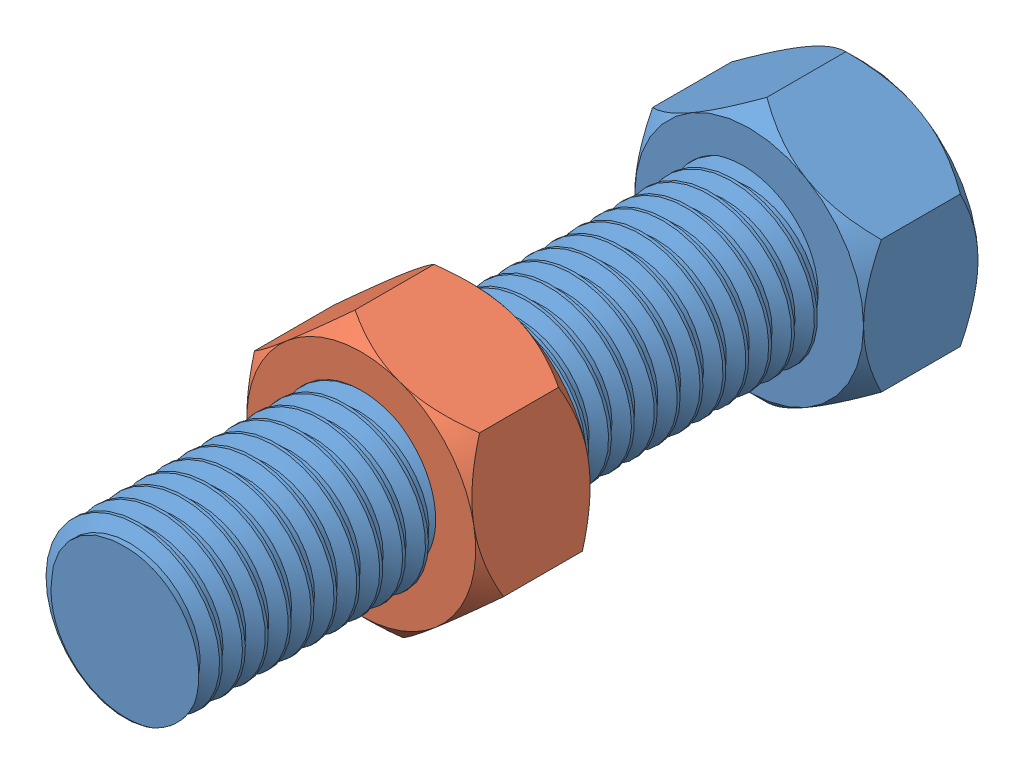
SolidWorks assembly Assem1, configuration Default. Lengths in mm.
Overall size (16.15 15.85 32.98).
2 component instances, 2 part files, 3 mates.
Components (placement in the parent):
- bolt-1: bolt [Default] at (11.5962 19.1086 10.4136) size (10 12.7 32.98)
- nut-1: nut [Default] at (11.5962 19.1086 27.3665) x (-0.648719 0.761028 0) z (0 0 1) size (10 12.7 5.69)
Mates (geometry in assembly coordinates):
- Concentric1: concentric: circle of bolt-1; circle of nut-1
- LimitDistance1: limit distance = 11.9529 mm: plane of nut-1 through (11.5962 19.1086 24.8665) normal (0 0 -1); plane of bolt-1 through (11.5962 19.1086 12.9136) normal (0 0 1)
- Screw2: screw = 1: cylinder of bolt-1 through (11.5962 19.1086 40.4136) axis (0 0 -1) radius 3; cylinder of nut-1 through (11.5962 19.1086 29.8665) axis (0 0 -1) radius 3
